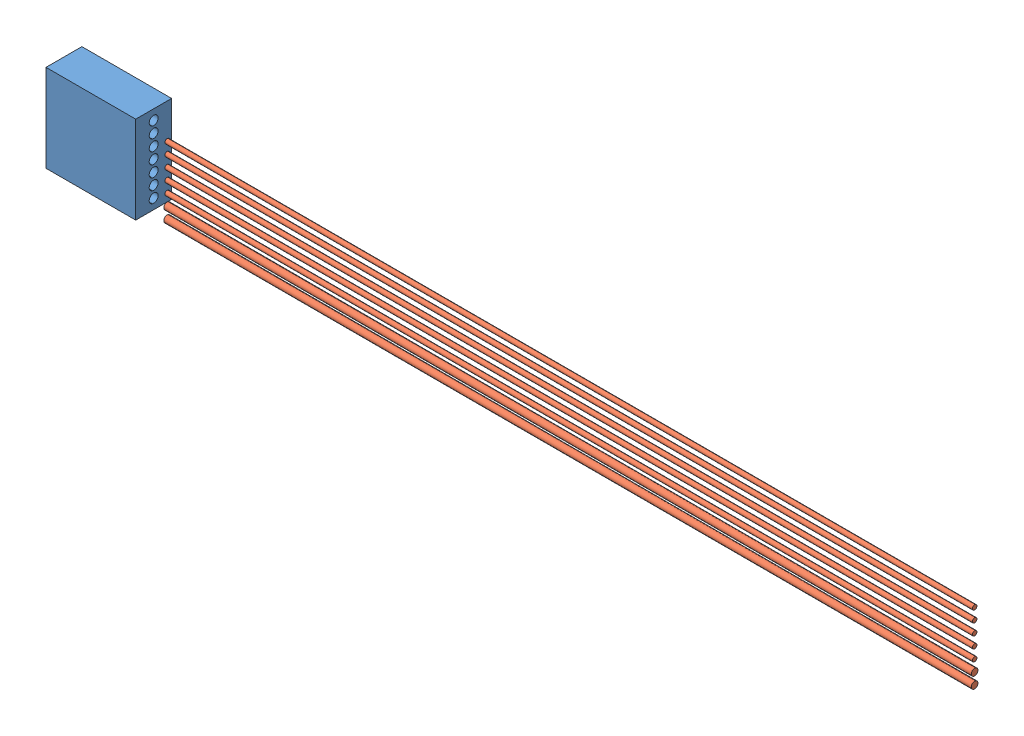
SolidWorks assembly Harness_21-CABLE_REALOP_ONE_ASSEMBLY, configuration AnnotateFlattenedRoute1 - Default. Lengths in mm.
Overall size (101.5 10.25 4).
3 component instances, 3 part files, 1 mates.
Components (placement in the parent):
- 7_PIN-1: 7_PIN [Default] at (-11.5 -7.625 2) x (0 -1 0) z (1 0 0) size (9.75 4 20)
- Cable^Harness_21-CABLE_REALOP_ONE_ASSEMBLY-1: Cable^Harness_21-CABLE_REALOP_ONE_ASSEMBLY [Default] at origin size (92.76 41.66 80.91) (suppressed, hidden, virtual)
- Flattened_Cable^Harness_21-CABLE_REALOP_ONE_ASSEMBLY-1: Flattened_Cable^Harness_21-CABLE_REALOP_ONE_ASSEMBLY [Default] at origin (virtual)
Mates (geometry in assembly coordinates):
- Coincident871: coincident anti-aligned: plane of X_AND_Y_SOLAR_ARRAYS-3 through (176.3175 -31.2025 191.5832) normal (0 1 0); plane of 7_PIN-1 through (50.0675 -31.2025 252.5832) normal (0 -1 0)
